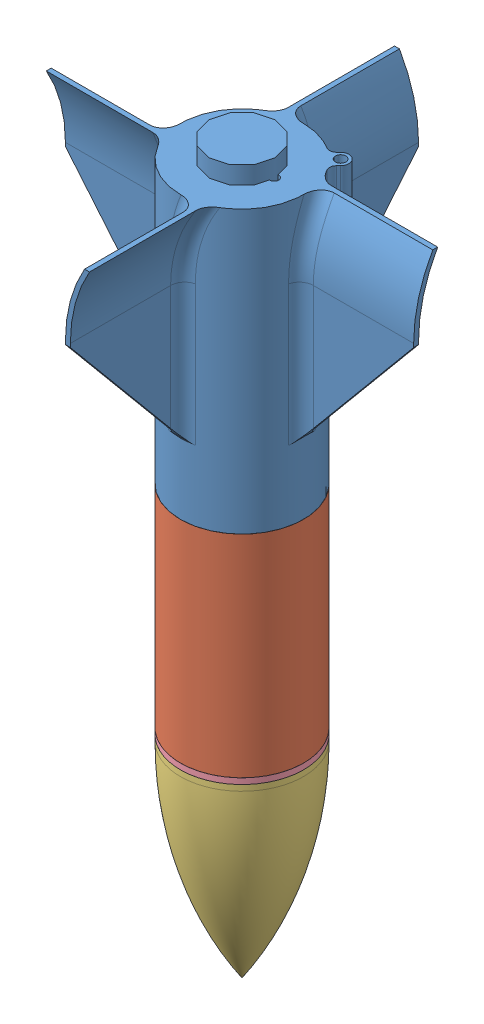
SolidWorks assembly rocket, configuration Default. Lengths in mm.
Overall size (125.73 256.1 125.73).
4 component instances, 4 part files, 6 mates.
Components (placement in the parent):
- 1.75inx18mm Twister Fincan-1: 1.75inx18mm Twister Fincan [Default] at (29.9665 46.221 107.85) size (125.73 107.95 125.73)
- 1.75in body tube-1: 1.75in body tube [Default] at (29.9665 33.521 107.85) x (-0.448237 0 -0.893915) z (-0.893915 0 0.448237) size (44.45 101.6 44.45)
- 1.75in Nosecone Ogive-1: 1.75in Nosecone Ogive [Default] at (29.9665 -70.179 107.85) x (-0.387064 0 0.922053) z (0.922053 0 0.387064) size (44.45 76.2 44.45)
- 1.75in Nosecone Coupler-1: 1.75in Nosecone Coupler [Default] at (29.9665 -70.179 107.85) x (-0.98017 0 0.19816) z (0.19816 0 0.98017) size (44.45 14.8 44.45)
Mates (geometry in assembly coordinates):
- Concentric1: concentric aligned: cylinder of 1.75inx18mm Twister Fincan-1 through (29.9665 8.121 107.85) axis (0 1 0) radius 21.175; cylinder of 1.75in body tube-1 through (29.9665 33.521 107.85) axis (0 1 0) radius 21.1201
- Coincident1: coincident anti-aligned: plane of 1.75inx18mm Twister Fincan-1 through (29.9665 8.121 107.85) normal (0 -1 0); plane of 1.75in body tube-1 through (20.0045 8.121 87.9828) normal (0 1 0)
- Coincident2: coincident anti-aligned: plane of 1.75in Nosecone Ogive-1 through (29.3521 -70.179 109.3138) normal (0 1 0); plane of 1.75in Nosecone Coupler-1 through (8.1823 -70.179 112.2541) normal (0 -1 0)
- Concentric2: concentric aligned: cylinder of 1.75in Nosecone Ogive-1 through (29.9665 -70.179 107.85) axis (0 1 0) radius 22.225; cylinder of 1.75in Nosecone Coupler-1 through (29.9665 -70.179 107.85) axis (0 1 0) radius 22.225
- Concentric3: concentric aligned: cylinder of 1.75in body tube-1 through (29.9665 33.521 107.85) axis (0 1 0) radius 21.1836; cylinder of 1.75in Nosecone Coupler-1 through (29.9665 -70.179 107.85) axis (0 1 0) radius 21.0693
- Coincident3: coincident anti-aligned: plane of 1.75in body tube-1 through (20.4713 -68.079 88.9137) normal (0 -1 0); plane of 1.75in Nosecone Coupler-1 through (9.3151 -68.079 112.0251) normal (0 1 0)
